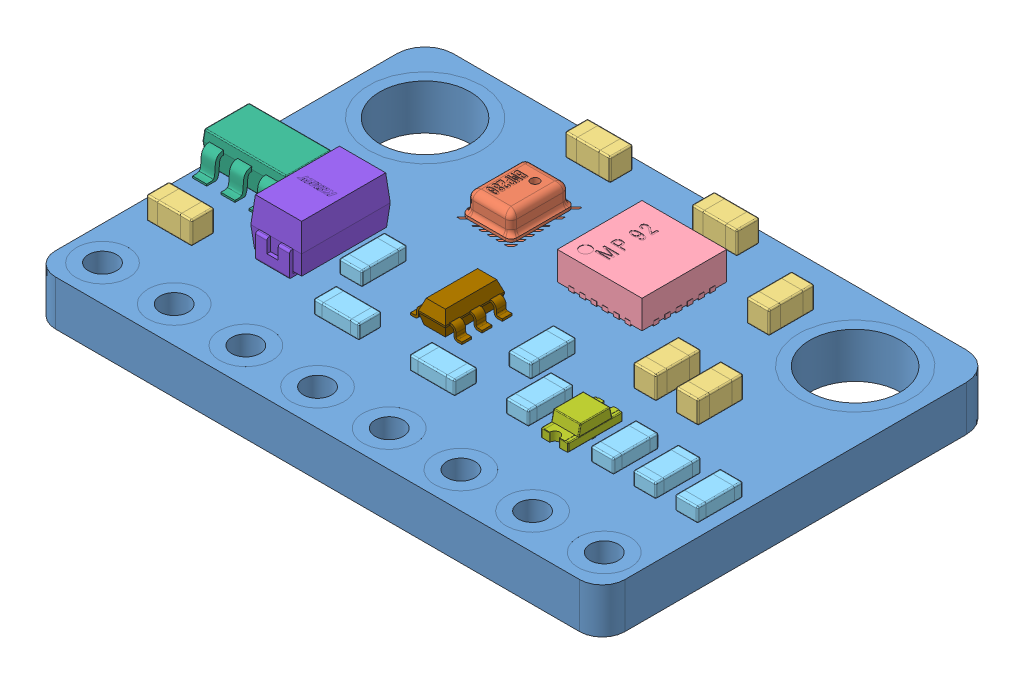
SolidWorks assembly GY-91_MPU9250+BMP280 - Basic, configuration Default. Lengths in mm.
Overall size (20.23 3.37 13.9).
21 component instances, 9 part files, 62 mates.
Components (placement in the parent):
- GY-91 Base-1: GY-91 Base [Default] at origin size (20.18 1.6 13.9)
- BMP280-1: BMP280 [По умолчанию] at (5.7995 1.42 -8.9272) x (0 0 1) z (-1 0 0) size (2.5 1 2)
- cap_603-1: cap_603 [Default] at (-0.5134 1.6 -2.0703) size (1.6 0.8 0.8)
- MPU9250-1: MPU9250 [Default] at (10.201 1.65 -8.9162) x (0 0 1) z (-1 0 0) size (3.02 1.05 3.02)
- res_603-1: res_603 [Default] at (5.3391 1.6 -2.1448) size (1.6 0.5 0.8)
- SOT23-5-1: SOT23-5 [Default] at (0.2503 1.495 -5.6099) x (0 0 1) z (0 1 0) size (2.91 3.01 1.23)
- Surface Mount Chip LED 3.2x1.6mm-1: Surface Mount Chip LED 3.2x1.6mm [Default] at (14.0926 1.606 -2.4124) x (0 0 -1) z (0 1 0) size (1.92 0.96 0.72)
- T10uF-1: T10uF [Default] at (-2.3637 -0.4413 -3.6504) x (0 0 -1) z (1 0 0) size (3.4 1.8 1.8)
- cap_603-2: cap_603 [Default] at (6.5671 2.4 -11.4227) x (-1 0 0) z (0 0 1) size (1.6 0.8 0.8)
- cap_603-3: cap_603 [Default] at (11.0567 2.4 -11.4227) x (-1 0 0) z (0 0 1) size (1.6 0.8 0.8)
- cap_603-4: cap_603 [Default] at (13.2687 1.6 -11.1516) x (0 0 1) z (-1 0 0) size (1.6 0.8 0.8)
- cap_603-5: cap_603 [Default] at (13.2687 2.4 -5.541) x (0 0 -1) z (-1 0 0) size (1.6 0.8 0.8)
- cap_603-6: cap_603 [Default] at (14.768 1.6 -7.141) x (0 0 1) z (-1 0 0) size (1.6 0.8 0.8)
- res_603-2: res_603 [Default] at (4.5594 2.1 -3.8308) x (0 0 -1) z (-1 0 0) size (1.6 0.5 0.8)
- res_603-3: res_603 [Default] at (10.3516 2.1 -2.1255) x (-1 0 0) z (0 0 1) size (1.6 0.5 0.8)
- res_603-4: res_603 [Default] at (10.3923 2.1 -3.9897) x (0 0 -1) z (-1 0 0) size (1.6 0.5 0.8)
- res_603-5: res_603 [Default] at (11.7903 2.1 -2.5005) x (0 0 -1) z (-1 0 0) size (1.6 0.5 0.8)
- res_603-6: res_603 [Default] at (14.7728 2.1 -2.5328) x (0 0 -1) z (-1 0 0) size (1.6 0.5 0.8)
- res_603-7: res_603 [Default] at (16.2723 2.1 -2.5328) x (0 0 -1) z (-1 0 0) size (1.6 0.5 0.8)
- res_603-8: res_603 [Default] at (17.7572 2.1 -2.5328) x (0 0 -1) z (-1 0 0) size (1.6 0.5 0.8)
- SOT23-6-1-1: SOT23-6-1 [Default] at (8.6954 1.6 -4.0236) x (0 0 -1) z (0 1 0) size (2.1 1.82 0.82)
Mates (geometry in assembly coordinates):
- Coincident1: coincident aligned: plane of GY-91 Base-1 through (0 0 0) normal (0 0 1)
- Coincident2: coincident aligned: plane of GY-91 Base-1 through (0 0 0) normal (0 1 0)
- Coincident3: coincident aligned: plane of GY-91 Base-1 through (0 0 0) normal (1 0 0)
- Coincident4: coincident anti-aligned: plane of GY-91 Base-1 through (18.18 1.6 0.47) normal (0 1 0); plane of MPU9250-1 through (10.201 1.6 -8.9162) normal (0 -1 0)
- Parallel1: parallel aligned: plane of GY-91 Base-1 through (17.98 1.6 -12.63) normal (0 0 -1); plane of MPU9250-1 through (11.701 1.65 -10.4162) normal (0 0 -1)
- Lock1: lock: unknown of GY-91 Base-1; unknown of MPU9250-1
- Coincident7: coincident aligned: plane of GY-91 Base-1 through (18.18 1.6 0.47) normal (0 1 0); plane of BMP280-1 through (5.7995 1.6 -8.9272) normal (0 1 0)
- Parallel3: parallel aligned: plane of GY-91 Base-1 through (17.98 1.6 -12.63) normal (0 0 -1); plane of BMP280-1 through (5.1245 1.7 -10.0522) normal (0 0 -1)
- Lock2: lock: unknown of GY-91 Base-1; unknown of BMP280-1
- Coincident9: coincident anti-aligned: plane of GY-91 Base-1 through (18.18 1.6 0.47) normal (0 1 0); plane of T10uF-1 through (4.111 1.6 -2.9462) normal (0 -1 0)
- Parallel4: parallel aligned: line of GY-91 Base-1 through (-0.4 1.6 1.27) axis (1 0 0); line of T10uF-1 through (2.311 2.45 -2.9462) axis (1 0 0)
- Lock3: lock: unknown of GY-91 Base-1; unknown of T10uF-1
- Coincident13: coincident anti-aligned: plane of GY-91 Base-1 through (18.18 1.6 0.47) normal (0 1 0); plane of SOT23-5-1 through (-1.2497 1.6 -4.8474) normal (0 -1 0)
- Parallel7: parallel anti-aligned: line of SOT23-5-1 through (1.7145 2.6642 -4.8604) axis (0 0 -1); line of GY-91 Base-1 through (-1.2 1.6 -11.63) axis (0 0 1)
- Lock4: lock: unknown of GY-91 Base-1; unknown of SOT23-5-1
- Coincident15: coincident anti-aligned: plane of GY-91 Base-1 through (18.18 1.6 0.47) normal (0 1 0); plane of Surface Mount Chip LED 3.2x1.6mm-1 through (13.1326 1.6 -3.2524) normal (0 -1 0)
- Parallel8: parallel aligned: line of GY-91 Base-1 through (18.98 1.6 0.47) axis (0 0 -1); line of Surface Mount Chip LED 3.2x1.6mm-1 through (14.0626 1.906 -2.4424) axis (0 0 -1)
- Lock5: lock: unknown of GY-91 Base-1; unknown of Surface Mount Chip LED 3.2x1.6mm-1
- Coincident21: coincident anti-aligned: plane of GY-91 Base-1 through (18.18 1.6 0.47) normal (0 1 0); plane of cap_603-1 through (-0.5134 1.6 -2.0703) normal (0 -1 0)
- Parallel10: parallel aligned: plane of GY-91 Base-1 through (-1.2 1.6 -11.63) normal (-1 0 0); plane of cap_603-1 through (-0.5134 2.4 -2.0703) normal (-1 0 0)
- Lock6: lock: unknown of GY-91 Base-1; plane of cap_603-1 through (0 0 0) normal (0 0 1)
- Coincident24: coincident anti-aligned: plane of GY-91 Base-1 through (18.18 1.6 0.47) normal (0 1 0); plane of res_603-1 through (5.3391 1.6 -2.1448) normal (0 -1 0)
- Parallel12: parallel aligned: plane of res_603-1 through (5.6391 2.1 -2.1448) normal (0 0 1); plane of GY-91 Base-1 through (-0.4 1.6 1.27) normal (0 0 1)
- Lock7: lock: unknown of GY-91 Base-1; unknown of res_603-1
- Coincident261: coincident anti-aligned: plane of GY-91 Base-1 through (18.18 1.6 0.47) normal (0 1 0); plane of cap_603-2 through (6.5671 1.6 -11.4227) normal (0 -1 0)
- Coincident271: coincident anti-aligned: plane of GY-91 Base-1 through (18.18 1.6 0.47) normal (0 1 0); plane of cap_603-3 through (11.0567 1.6 -11.4227) normal (0 -1 0)
- Coincident281: coincident anti-aligned: plane of GY-91 Base-1 through (18.18 1.6 0.47) normal (0 1 0); plane of cap_603-4 through (13.2687 1.6 -11.1516) normal (0 -1 0)
- Coincident291: coincident anti-aligned: plane of GY-91 Base-1 through (18.18 1.6 0.47) normal (0 1 0); plane of cap_603-5 through (13.2687 1.6 -5.541) normal (0 -1 0)
- Coincident301: coincident anti-aligned: plane of GY-91 Base-1 through (18.18 1.6 0.47) normal (0 1 0); plane of cap_603-6 through (14.768 1.6 -7.141) normal (0 -1 0)
- Coincident311: coincident anti-aligned: plane of GY-91 Base-1 through (18.18 1.6 0.47) normal (0 1 0); plane of res_603-2 through (4.5594 1.6 -3.8308) normal (0 -1 0)
- Coincident321: coincident anti-aligned: plane of GY-91 Base-1 through (18.18 1.6 0.47) normal (0 1 0); plane of res_603-3 through (10.3516 1.6 -2.1255) normal (0 -1 0)
- Coincident331: coincident anti-aligned: plane of GY-91 Base-1 through (18.18 1.6 0.47) normal (0 1 0); plane of res_603-4 through (10.3923 1.6 -3.9897) normal (0 -1 0)
- Coincident341: coincident anti-aligned: plane of GY-91 Base-1 through (18.18 1.6 0.47) normal (0 1 0); plane of res_603-5 through (11.7903 1.6 -2.5005) normal (0 -1 0)
- Coincident351: coincident anti-aligned: plane of GY-91 Base-1 through (18.18 1.6 0.47) normal (0 1 0); plane of res_603-6 through (14.7728 1.6 -2.5328) normal (0 -1 0)
- Coincident361: coincident anti-aligned: plane of GY-91 Base-1 through (18.18 1.6 0.47) normal (0 1 0); plane of res_603-7 through (16.2723 1.6 -2.5328) normal (0 -1 0)
- Coincident371: coincident anti-aligned: plane of GY-91 Base-1 through (18.18 1.6 0.47) normal (0 1 0); plane of res_603-8 through (17.7572 1.6 -2.5328) normal (0 -1 0)
- Parallel13: parallel aligned: plane of GY-91 Base-1 through (-0.4 1.6 1.27) normal (0 0 1); plane of res_603-2 through (4.5594 1.6 -3.8308) normal (0 0 1)
- Lock8: lock: unknown of GY-91 Base-1; unknown of res_603-2
- Parallel14: parallel aligned: plane of GY-91 Base-1 through (-0.4 1.6 1.27) normal (0 0 1); plane of res_603-3 through (10.0516 1.6 -2.1255) normal (0 0 1)
- Lock9: lock: unknown of GY-91 Base-1; unknown of res_603-3
- Lock10: lock: unknown of GY-91 Base-1; unknown of res_603-4
- Parallel16: parallel aligned: plane of GY-91 Base-1 through (-0.4 1.6 1.27) normal (0 0 1); plane of res_603-5 through (11.7903 1.6 -2.5005) normal (0 0 1)
- Lock11: lock: unknown of GY-91 Base-1; unknown of res_603-5
- Parallel17: parallel aligned: plane of GY-91 Base-1 through (-0.4 1.6 1.27) normal (0 0 1); plane of res_603-6 through (14.7728 1.6 -2.5328) normal (0 0 1)
- Lock12: lock: unknown of GY-91 Base-1; unknown of res_603-6
- Coincident46: coincident aligned: plane of res_603-6 through (14.7728 1.6 -2.5328) normal (0 0 1); plane of res_603-7 through (16.2723 1.6 -2.5328) normal (0 0 1)
- Lock13: lock: unknown of GY-91 Base-1; unknown of res_603-7
- Coincident47: coincident aligned: plane of res_603-7 through (16.2723 1.6 -2.5328) normal (0 0 1); plane of res_603-8 through (17.7572 1.6 -2.5328) normal (0 0 1)
- Lock14: lock: unknown of GY-91 Base-1; unknown of res_603-8
- Parallel18: parallel aligned: plane of cap_603-5 through (13.2687 1.6 -5.541) normal (0 0 1); plane of res_603-5 through (11.7903 1.6 -2.5005) normal (0 0 1)
- Lock15: lock: unknown of GY-91 Base-1; unknown of cap_603-5
- Coincident49: coincident aligned: plane of cap_603-5 through (13.2687 1.6 -5.541) normal (0 0 1); plane of cap_603-6 through (15.568 2.4 -5.541) normal (0 0 1)
- Lock16: lock: unknown of GY-91 Base-1; unknown of cap_603-6
- Parallel19: parallel aligned: plane of GY-91 Base-1 through (18.98 1.6 0.47) normal (1 0 0); plane of cap_603-2 through (6.5671 1.6 -11.4227) normal (1 0 0)
- Lock17: lock: unknown of GY-91 Base-1; unknown of cap_603-2
- Coincident51: coincident aligned: plane of cap_603-2 through (6.1671 1.6 -11.4227) normal (0 0 1); plane of cap_603-3 through (10.6567 1.6 -11.4227) normal (0 0 1)
- Lock18: lock: unknown of GY-91 Base-1; unknown of cap_603-3
- Coincident52: coincident aligned: plane of cap_603-4 through (13.2687 2.4 -10.7516) normal (-1 0 0); plane of cap_603-5 through (13.2687 1.6 -5.941) normal (-1 0 0)
- Lock19: lock: unknown of GY-91 Base-1; unknown of cap_603-4
- Coincident53: coincident anti-aligned: plane of GY-91 Base-1 through (18.18 1.6 0.47) normal (0 1 0); plane of SOT23-6-1-1 through (7.5048 1.6 -3.6902) normal (0 -1 0)
- Parallel20: parallel anti-aligned: line of GY-91 Base-1 through (17.98 1.6 -12.63) axis (-1 0 0); line of SOT23-6-1-1 through (7.5048 2.0381 -3.6902) axis (1 0 0)
- Lock20: lock: unknown of GY-91 Base-1; unknown of SOT23-6-1-1
